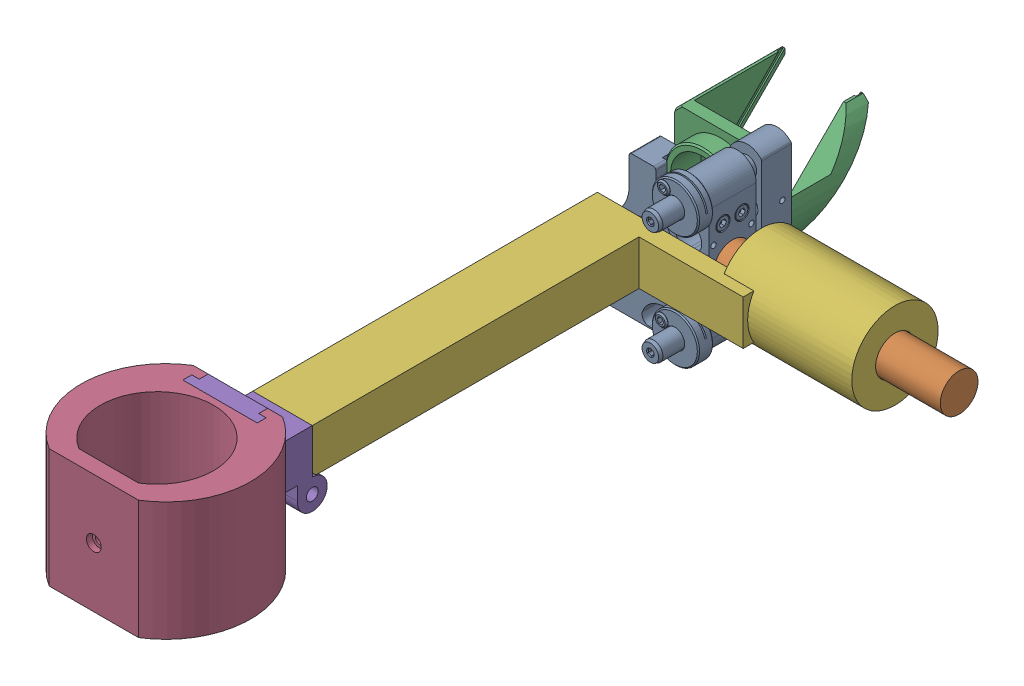
SolidWorks assembly lens_assy_1, configuration Default. Lengths in mm.
Overall size (130.05 53.98 244.98).
8 component instances, 6 part files, 0 mates.
Components (placement in the parent):
- Mirror holder assembled_1-1: Mirror holder assembled_1 [Default] at (-2.875 78.0363 -211.1891) x (0 1 0) z (0 0 1) size (53.98 128.56 42.58)
  - Newport-U100-A3H.stp_1-1: Newport-U100-A3H.stp_1 [Default] at (-172.1028 -102.6999 -107.2719) size (53.97 53.98 42.58)
  - Mirror shaft_1-1: Mirror shaft_1 [Default] at (-78.0363 -104.445 43.1749) x (-0.381849 0 -0.924225) z (0.924225 0 -0.381849) size (12.68 76.17 12.68)
- Mirror holder attachment__X2_98108a2d_X0_-1: Mirror holder attachment__X2_98108a2d_X0_ [Default] at (14.8645 0 -183.1242) x (-1 0 0) z (0 0 -1) size (36.11 31.26 40.64)
- lens_collar_hinge_assy_1-1: lens_collar_hinge_assy_1 [Default] at origin size (108.48 40 203.73)
  - len_mount_hinge1_1-1: len_mount_hinge1_1 [Default] at origin size (56.97 40 48.43)
  - len_mount_hinge2_1-1: len_mount_hinge2_1 [Default] at (0 0 -27.2143) x (0 0 -1) z (1 0 0) size (26 37.5 25)
  - len_mount_hinge3_1-1: len_mount_hinge3_1 [Default] at (0 0 -42.2143) x (0 0 -1) z (1 0 0) size (145.3 32 90)
